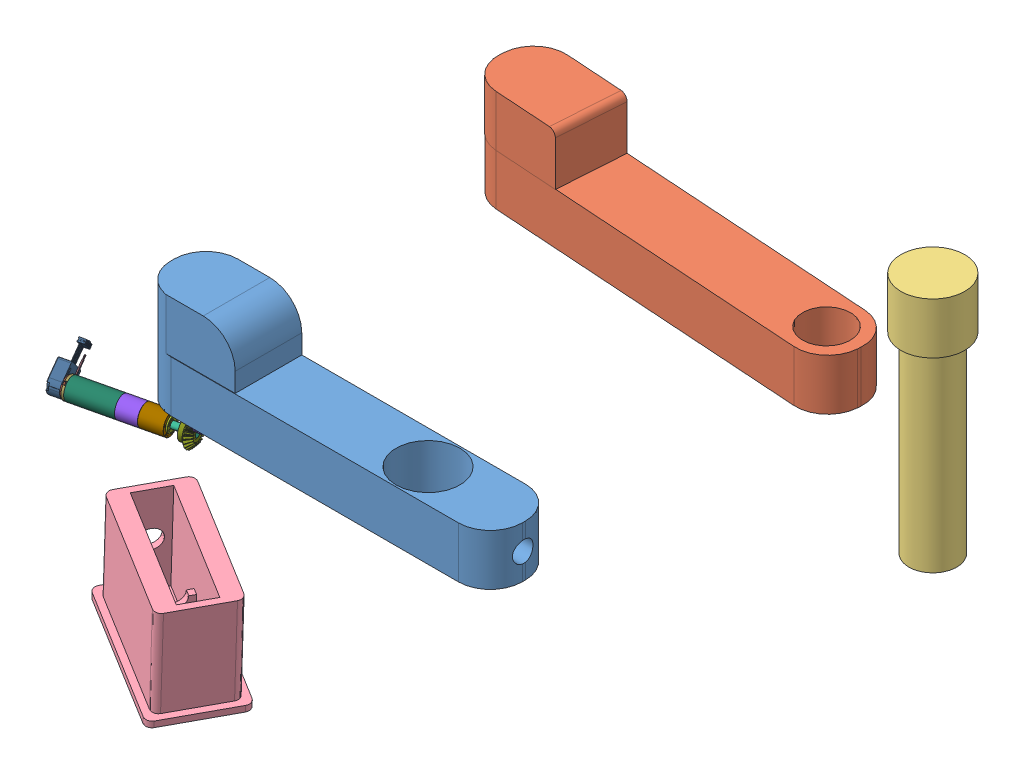
SolidWorks assembly Assem1, configuration Default. Lengths in mm.
Overall size (1535.81 1224.73 269).
21 component instances, 17 part files, 4 mates.
Components (placement in the parent):
- Arm1-1: Arm1 [Default] at (136.1784 0 620.9841) size (550 200 105)
- Arm2-1: Arm2 [Default] at (715.2928 576.7393 679.7318) x (0.9978 0 0.066291) z (-0.066291 0 0.9978) size (600 180 105.46)
- Arm3-1: Arm3 [Default] at (1182.0968 788.3223 751.9697) x (0.174656 0 0.984629) z (0.984629 0 -0.174656) size (100 380 100)
- Base2-1: Base2 [Default] at (-108.2518 -331.5476 651.9837) x (0.865125 -0.123389 0.486142) z (-0.491149 -0.01198 0.870993) size (230 160 125)
- Motor with pinion gear system-1: Motor with pinion gear system [Default] at (-107.6116 117.0977 562.4663) x (-0.973689 0 0.227883) z (0.177823 -0.625371 0.759796) size (227.29 80.78 96.88)
  - MotorFinal-1: MotorFinal [默认] at (37.8954 93.4939 154.8939) size (188.9 32 73.2)
    - 0_1 (2).stp-1: 0_1 (2).stp [Default] at origin size (188.9 32 73.2)
      - 0.stp-1: 0.stp [Default] at origin size (12 3 3)
      - 0-0.stp-1: 0-0.stp [Default] at origin size (36 10 10.01)
      - 0-1.stp-1: 0-1.stp [Default] at origin size (6 22 22)
      - 0-2.stp-1: 0-2.stp [Default] at origin size (29.95 32 32)
      - 0-3.stp-1: 0-3.stp [Default] at origin size (33.59 32 32)
      - 0-4.stp-1: 0-4.stp [Default] at origin size (20.95 30 72.2)
      - 0-5.stp-1: 0-5.stp [Default] at origin size (2.3 29.7 30)
      - 0-6.stp-1: 0-6.stp [Default] at origin size (3.5 31.47 31.66)
      - 0-7.stp-1: 0-7.stp [Default] at origin size (6.99 3.52 29.03)
      - 0-8.stp-1: 0-8.stp [Default] at origin size (2.9 31.8 31.3)
      - 0-9.stp-1: 0-9.stp [Default] at origin size (66.2 32 32)
  - Pinion Gear System-1: Pinion Gear System [Default] at (325.5131 -805.982 1229.2721) x (0.999245 -0.024303 0.030325) z (0 -0.780327 -0.625371) size (55.67 60.71 59.99)
    - straight bevel gear_am-1: straight bevel gear_am [Metric - Straight bevel gear 2M 20GT 20PT 20PA 12FW ---20O30H30MD10S1] at (-367.4444 -1387.6419 -30.0001) x (-0.999245 0.038861 0) z (-0.024303 -0.624899 -0.780327) size (19.85 42.67 42.67)
    - straight bevel pinion_am-1: straight bevel pinion_am [Metric - Straight bevel pinion 2M20PT 20GT 20PA 12FW ---20O35H30MD10N] at (-389.5287 -1386.783 -7.8991) x (0 0 -1) z (0.986616 0.163058 0) size (19.85 42.67 42.67)
Mates (geometry in assembly coordinates):
- Concentric1: concentric aligned: cylinder of Arm1-1 through (-83.8216 -40 620.9841) axis (0 1 0) radius 5; cylinder of Motor with pinion gear system-1/Pinion Gear System-1/straight bevel pinion_am-1 through (-83.8216 -60.6234 620.9841) axis (0 1 0) radius 5
- Coincident1: coincident aligned: plane of Arm1-1 through (-83.8216 -40 620.9841) normal (0 -1 0); circle of Motor with pinion gear system-1/Pinion Gear System-1/straight bevel pinion_am-1
- Perpendicular1: perpendicular: line of Arm1-1 through (-83.8216 -40 620.9841) axis (0 1 0); line of Motor with pinion gear system-1/MotorFinal-1/0_1 (2).stp-1/0-3.stp-1 through (-162.9964 -52.7243 639.5143) axis (0.973689 0 -0.227883)
- Coincident3: coincident anti-aligned: plane of Arm1-1 through (136.1784 0 620.9841) normal (0 -1 0)
